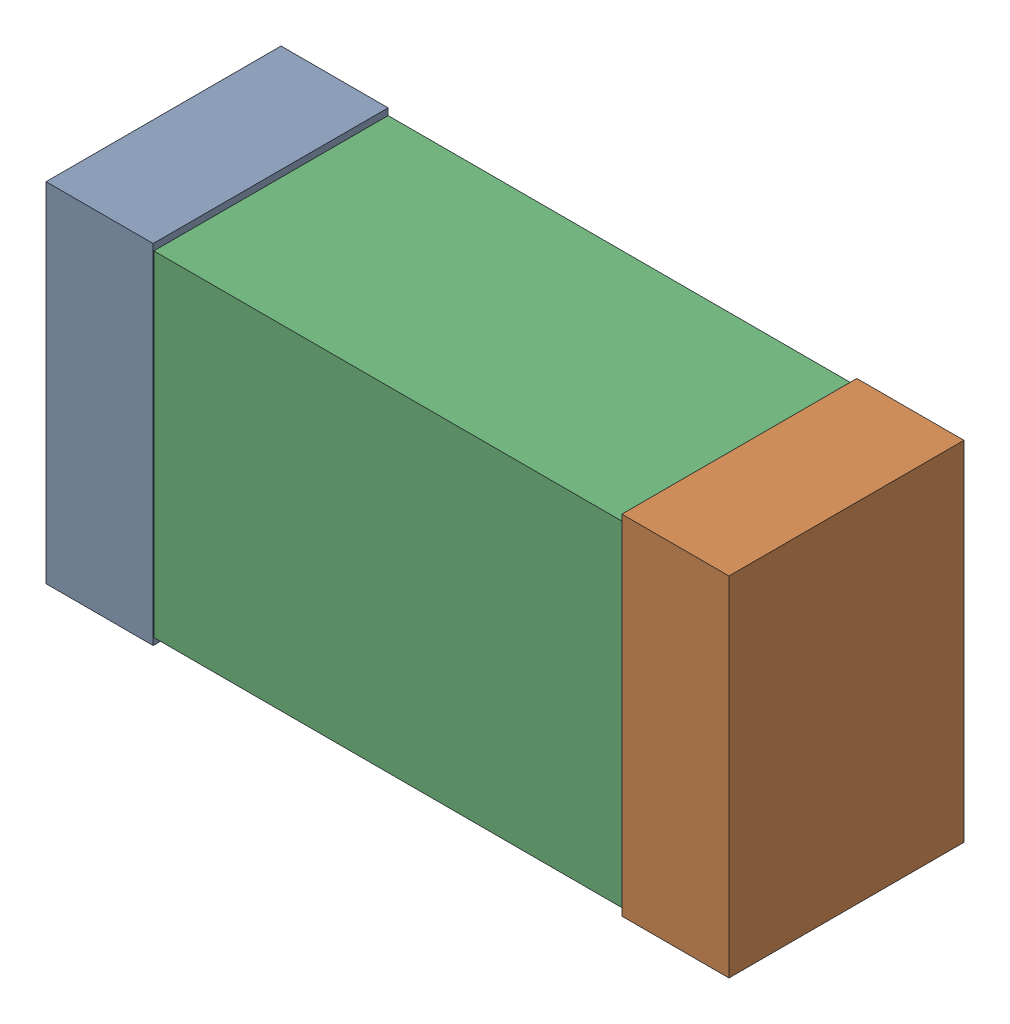
SolidWorks assembly C7, configuration Default. Lengths in mm.
Overall size (1.02 0.52 0.35).
6 component instances, 2 part files, 0 mates.
Components (placement in the parent):
- 870940480-1: 870940480 [Default] at (13.794 4.064 0) size (0.16 0.52 0.35)
  - Extruded-1: Extruded [Default] at origin size (0.16 0.52 0.35)
- 870940480-2: 870940480 [Default] at (14.654 4.064 0) size (0.16 0.52 0.35)
  - Extruded-1: Extruded [Default] at origin size (0.16 0.52 0.35)
- 870940640-1: 870940640 [Default] at (14.224 4.064 0) size (1 0.5 0.35)
  - Extruded_2-1: Extruded_2 [Default] at origin size (1 0.5 0.35)
